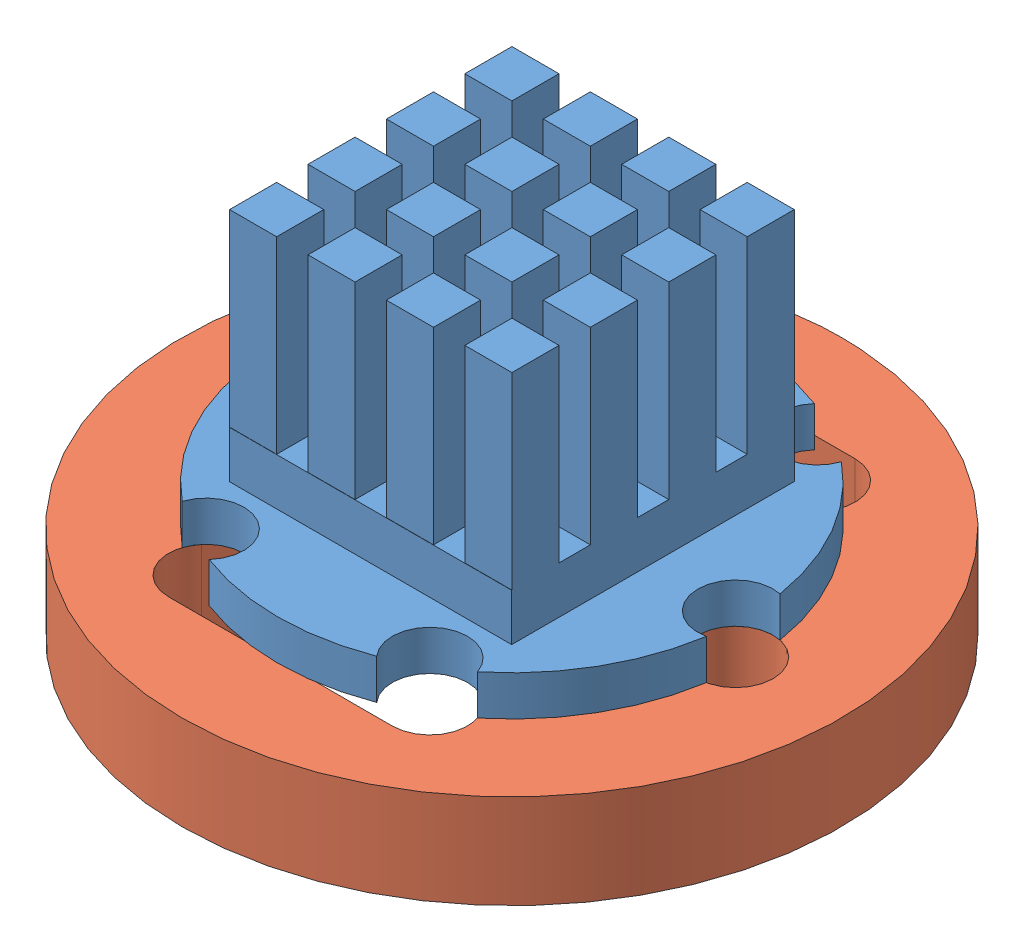
SolidWorks assembly UV_Star_rev1, configuration Default. Lengths in mm.
Overall size (28 15.7 28).
2 component instances, 2 part files, 0 mates.
Components (placement in the parent):
- UV_Star-1: UV_Star [Default] at (7.1147 7.1687 17.6253) size (19.65 14.5 19.9)
- UV_Star_Holder-1: UV_Star_Holder [Default] at origin size (28 4 28)
